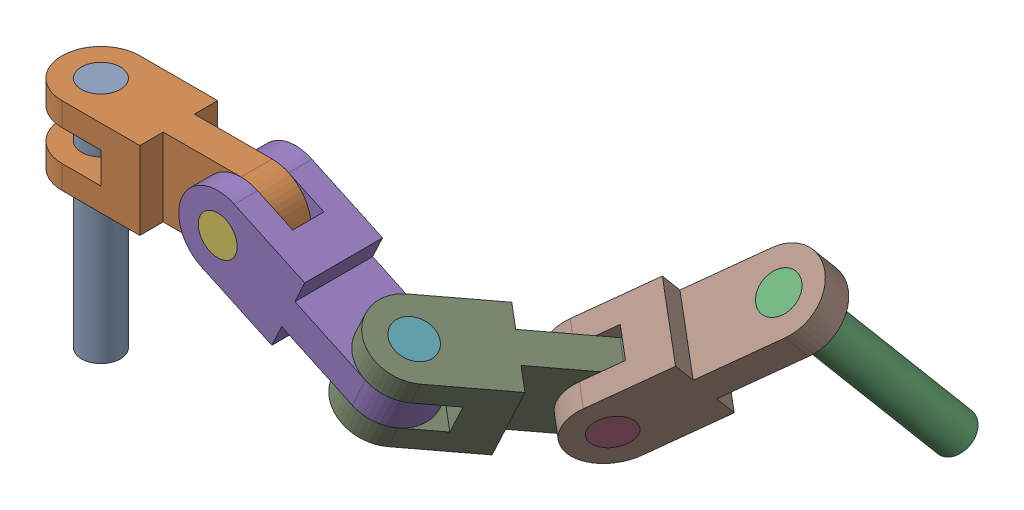
SolidWorks assembly Assemblage1, configuration Défaut. Lengths in mm.
Overall size (743.06 325.54 535.4).
9 component instances, 3 part files, 24 mates.
Components (placement in the parent):
- long_pin-1: long_pin [Default] at origin size (50 300 50)
- chain_link-3: chain_link [Default] at (100 -50 -0.0377) x (0.000377 0 1) z (0 -1 0) size (100 300 100)
- long_pin-2: long_pin [Default] at (614.1785 -59.9477 -256.8203) x (0.991516 0.117314 0.055977) z (0.030616 -0.629302 0.776558) size (50 300 50)
- short_pin-1: short_pin [Default] at (448.036 -165.695 -192.6784) x (0.577058 0.765207 -0.285418) z (-0.339882 0.542782 0.768029) size (50 100 50)
- chain_link-6: chain_link [Default] at (290.6308 -92.2618 -0.1097) x (0.422618 0.906308 -0.00016) z (0.000377 0 1) size (100 300 100)
- short_pin-2: short_pin [Default] at (199.9811 -50 -50.0755) x (0.998061 0.062237 -0.000377) z (-0.062237 0.998061 0.000023) size (50 100 50)
- short_pin-3: short_pin [Default] at (402.3924 -89.2083 -0.1519) x (0.906293 -0.42261 0.005834) z (-0.00522 0.00261 0.999983) size (50 100 50)
- chain_link-7: chain_link [Default] at (550.9361 -129.1586 -216.6925) x (-0.126327 0.768256 0.627555) z (0.74262 -0.346189 0.573296) size (100 300 100)
- chain_link-8: chain_link [Default] at (433.2143 -158.764 -82.0787) x (0.74262 -0.346189 0.573296) z (-0.422618 -0.906308 0.00016) size (100 300 100)
Mates (geometry in assembly coordinates):
- Coaxiale7: concentric anti-aligned: cylinder of long_pin-1 through (0 -300 0) axis (0 1 0) radius 25; cylinder of chain_link-3 through (0 0 0) axis (0 -1 0) radius 25
- Coïncidente2: coincident aligned: plane of long_pin-1 through (0 0 0) normal (0 1 0); plane of chain_link-3 through (0 0 0) normal (0 1 0)
- Perpendiculaire1: perpendicular: cylinder of long_pin-1 through (0 -300 0) axis (0 1 0) radius 25; line of chain_link-3 through (200.0075 0 19.9245) axis (-1 0 0.000377)
- Perpendiculaire2: perpendicular: cylinder of long_pin-1 through (0 -300 0) axis (0 1 0) radius 25; line of chain_link-3 through (200.0075 0 19.9245) axis (-1 0 0.000377)
- Coïncidente3: coincident anti-aligned: plane of chain_link-3 through (199.9924 -50 -20.0755) normal (-0.000377 0 -1); plane of chain_link-6 through (133.5461 -74.1845 -20.0504) normal (0.000377 0 1)
- Coïncidente4: coincident anti-aligned: plane of chain_link-3 through (200.0075 -50 19.9245) normal (0.000377 0 1); plane of chain_link-6 through (133.5612 -74.1845 19.9496) normal (-0.000377 0 -1)
- Coaxiale8: concentric aligned: cylinder of chain_link-3 through (199.9811 -50 -50.0755) axis (0.000377 0 1) radius 25; cylinder of chain_link-6 through (199.9811 -50 -50.0755) axis (0.000377 0 1) radius 25
- Angle1: planar angle = 2.70526 rad anti-aligned: plane of chain_link-6 through (311.7805 -46.9464 49.8823) normal (0.422618 0.906308 -0.00016); plane of chain_link-3 through (0 0 0) normal (0 1 0)
- Coaxiale9: concentric anti-aligned: cylinder of chain_link-6 through (199.9811 -50 -50.0755) axis (0.000377 0 1) radius 25; cylinder of short_pin-2 through (200.0189 -50 49.9245) axis (-0.000377 0 -1) radius 25
- Coïncidente6: coincident aligned: plane of chain_link-6 through (200.0189 -50 49.9245) normal (0.000377 0 1); plane of short_pin-2 through (200.0189 -50 49.9245) normal (0.000377 0 1)
- Coïncidente7: coincident anti-aligned: plane of chain_link-6 through (389.7139 -116.3975 -0.1471) normal (0.422618 0.906308 -0.00016); plane of chain_link-8 through (326.6065 -86.9679 12.1555) normal (-0.422618 -0.906308 0.00016)
- Coïncidente8: coincident anti-aligned: plane of chain_link-6 through (372.8092 -152.6498 -0.1407) normal (-0.422618 -0.906308 0.00016); plane of chain_link-8 through (309.7018 -123.2202 12.1619) normal (0.422618 0.906308 -0.00016)
- Coaxiale10: concentric anti-aligned: cylinder of chain_link-6 through (360.1306 -179.8391 -0.1359) axis (0.422618 0.906308 -0.00016) radius 25; cylinder of chain_link-8 through (402.3924 -89.2083 -0.1519) axis (-0.422618 -0.906308 0.00016) radius 25
- Coaxiale11: concentric anti-aligned: cylinder of short_pin-3 through (360.1306 -179.839 -0.1359) axis (0.422618 0.906308 -0.00016) radius 25; cylinder of chain_link-8 through (402.3924 -89.2083 -0.1519) axis (-0.422618 -0.906308 0.00016) radius 25
- Coïncidente9: coincident anti-aligned: circle of short_pin-3; plane of chain_link-8 through (360.1306 -179.839 -0.1359) normal (-0.422618 -0.906308 0.00016)
- Angle2: planar angle = 2.181662 rad anti-aligned: plane of chain_link-6 through (199.9811 -50 -50.0755) normal (-0.000377 0 -1); plane of chain_link-8 through (374.9524 -186.77 -110.7356) normal (-0.74262 0.346189 -0.573296)
- Coïncidente11: coincident anti-aligned: plane of chain_link-7 through (443.7465 -241.4163 -180.5177) normal (0.74262 -0.346189 0.573296); plane of chain_link-8 through (470.3146 -176.0807 -175.4795) normal (-0.74262 0.346189 -0.573296)
- Coïncidente12: coincident anti-aligned: plane of chain_link-7 through (473.4513 -255.2639 -157.5859) normal (-0.74262 0.346189 -0.573296); plane of chain_link-8 through (500.0194 -189.9282 -152.5476) normal (0.74262 -0.346189 0.573296)
- Coaxiale12: concentric aligned: cylinder of chain_link-7 through (448.036 -165.695 -192.6784) axis (0.74262 -0.346189 0.573296) radius 25; cylinder of chain_link-8 through (448.036 -165.695 -192.6784) axis (0.74262 -0.346189 0.573296) radius 25
- Coaxiale13: concentric anti-aligned: cylinder of short_pin-1 through (522.2981 -200.3139 -135.3487) axis (-0.74262 0.346189 -0.573296) radius 25; cylinder of chain_link-7 through (448.036 -165.695 -192.6784) axis (0.74262 -0.346189 0.573296) radius 25
- Coïncidente13: coincident aligned: plane of short_pin-1 through (448.036 -165.695 -192.6784) normal (-0.74262 0.346189 -0.573296); plane of chain_link-7 through (448.036 -165.695 -192.6784) normal (-0.74262 0.346189 -0.573296)
- Angle5: planar angle = 4.014257 rad anti-aligned: plane of chain_link-7 through (581.7507 -108.0553 -156.6499) normal (-0.126327 0.768256 0.627555); plane of chain_link-8 through (402.3924 -89.2083 -0.1519) normal (0.422618 0.906308 -0.00016)
- Coaxiale15: concentric aligned: cylinder of long_pin-2 through (652.0768 -290.4244 -445.0866) axis (-0.126327 0.768256 0.627555) radius 25; cylinder of chain_link-7 through (623.0215 -113.7257 -300.7491) axis (-0.126327 0.768256 0.627555) radius 25
- Coïncidente23: coincident aligned: plane of long_pin-2 through (614.1785 -59.9477 -256.8203) normal (-0.126327 0.768256 0.627555); plane of chain_link-7 through (614.1785 -59.9477 -256.8203) normal (-0.126327 0.768256 0.627555)
